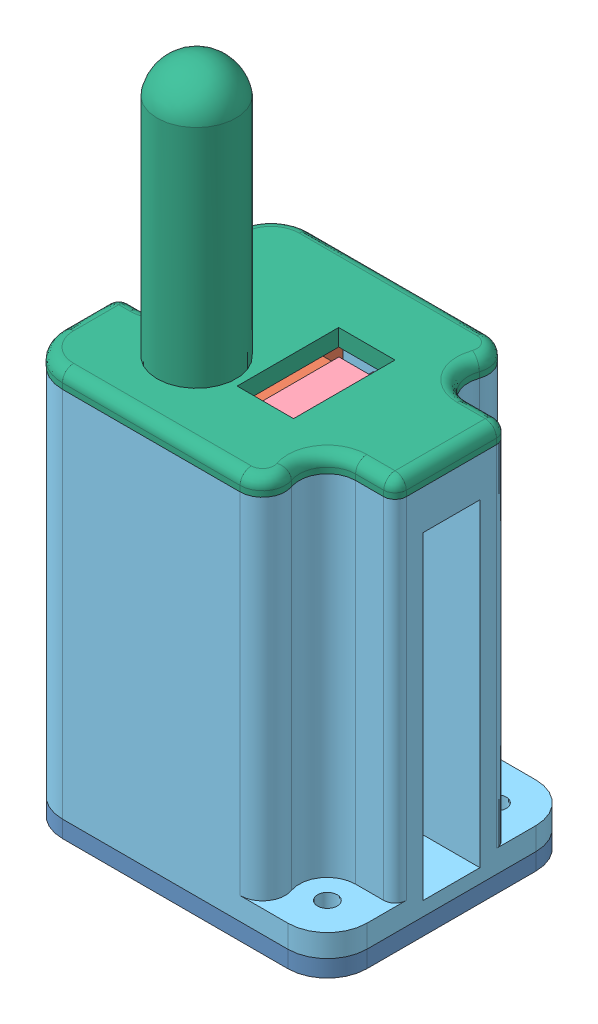
SolidWorks assembly modulo_baliza_Lora, configuration Predeterminado. Lengths in mm.
Overall size (54 118.05 44).
6 component instances, 6 part files, 9 mates.
Components (placement in the parent):
- base_baliza_LDR_LoRa-1: base_baliza_LDR_LoRa [Predeterminado] at (-52.1183 86.4998 -6.085) size (54 62 44)
- modulo_LoRa-1: modulo_LoRa [Predeterminado] at (-37.1183 153.6998 -10.085) x (0 -1 0) z (0 0 1) size (86.1 8 36)
- tiraLedWS2812-1: tiraLedWS2812 [Predeterminado] at (-14.5683 91.4998 -35.785) x (0 1 0) z (1 0 0) size (57.2 10.7 3)
- sensor LDR-1: sensor LDR [Predeterminado] at (-14.5683 148.6998 -16.585) x (0 0 -1) z (1 0 0) size (31.6 6.34 15)
- carcasa_modulo_baliza-1: carcasa_modulo_baliza [Predeterminado] at origin size (54 66 44)
- tapa_sup_antena-1: tapa_sup_antena [Predeterminado] at origin size (54 49.05 44)
Mates (geometry in assembly coordinates):
- Distancia1: distance = 15 mm aligned: plane of modulo_LoRa-1 through (-37.1183 153.6998 -10.085) normal (-1 0 0); plane of base_baliza_LDR_LoRa-1 through (-52.1183 89.4998 -13.085) normal (-1 0 0)
- Ancho1: width aligned: plane of base_baliza_LDR_LoRa-1 through (-45.1183 89.4998 -6.085) normal (0 0 1); plane of modulo_LoRa-1 through (-45.1183 89.4998 -50.085) normal (0 0 -1); plane of base_baliza_LDR_LoRa-1 through (-35.3183 153.6998 -10.085) normal (0 0 1); plane of modulo_LoRa-1 through (-35.3183 153.6998 -46.085) normal (0 0 -1)
- Coincidente1: coincident anti-aligned: plane of sensor LDR-1 through (-14.5683 148.6998 -16.585) normal (0 -1 0); plane of modulo_LoRa-1 through (-32.3183 148.6998 -15.085) normal (0 1 0)
- Distancia2: distance = 15 mm aligned: plane of base_baliza_LDR_LoRa-1 through (1.8817 89.4998 -13.085) normal (1 0 0); plane of tiraLedWS2812-1 through (-13.1183 91.4998 -35.785) normal (1 0 0)
- Ancho2: width anti-aligned: plane of base_baliza_LDR_LoRa-1 through (-45.1183 89.4998 -6.085) normal (0 0 1); plane of tiraLedWS2812-1 through (-45.1183 89.4998 -50.085) normal (0 0 -1); plane of base_baliza_LDR_LoRa-1 through (-11.5683 92.8998 -25.585) normal (0 0 1); plane of tiraLedWS2812-1 through (-11.5683 92.8998 -30.585) normal (0 0 -1)
- Distancia3: distance = 2 mm anti-aligned: plane of base_baliza_LDR_LoRa-1 through (-45.1183 89.4998 -13.085) normal (0 1 0); plane of tiraLedWS2812-1 through (-13.1183 91.4998 -35.785) normal (0 -1 0)
- Coincidente4: coincident anti-aligned: plane of tiraLedWS2812-1 through (-14.5683 91.4998 -35.785) normal (-1 0 0); plane of sensor LDR-1 through (-14.5683 150.4998 -16.585) normal (1 0 0)
- Ancho3: width anti-aligned: plane of sensor LDR-1 through (-14.5683 150.4998 -39.585) normal (0 0 -1); plane of tiraLedWS2812-1 through (-14.5683 150.4998 -16.585) normal (0 0 1); plane of sensor LDR-1 through (-11.5683 142.5998 -25.585) normal (0 0 1); plane of tiraLedWS2812-1 through (-11.5683 142.5998 -30.585) normal (0 0 -1)
- Coincidente5: coincident anti-aligned: plane of tiraLedWS2812-1 through (-13.1183 148.6998 -35.785) normal (0 1 0); plane of sensor LDR-1 through (-14.5683 148.6998 -16.585) normal (0 -1 0)
